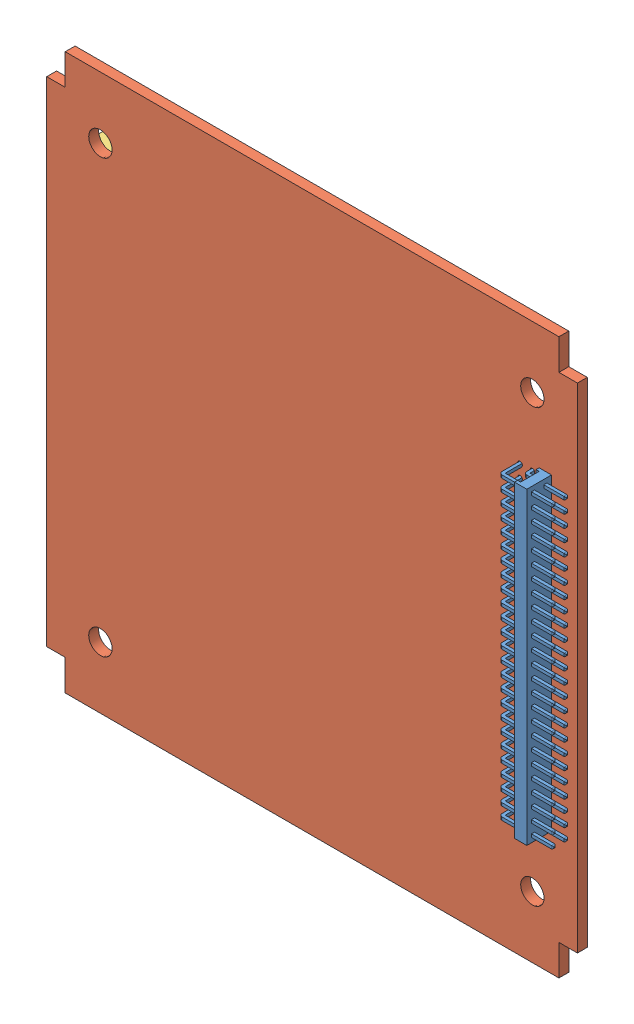
SolidWorks assembly B3_LDM_board, configuration ﾃﾞﾌｫﾙﾄ. Lengths in mm.
Overall size (86 90 16.2).
4 component instances, 3 part files, 9 mates.
Components (placement in the parent):
- B3_50pinL-2: B3_50pinL [Default] at (33.5663 23.7961 119.8153) x (0 -1 0) z (0 0 1) size (50 8.75 7)
- B3_internal_board_LDM-1: B3_internal_board_LDM [ﾃﾞﾌｫﾙﾄ] at (39.7663 43.7961 118.2153) size (86 90 1.6)
- MMCX002-1: MMCX002 [ﾃﾞﾌｫﾙﾄ] at (-44.7337 4.2961 113.4153) x (0 0 1) z (0 1 0) size (10.6 8.66 27)
- MMCX002-2: MMCX002 [ﾃﾞﾌｫﾙﾄ] at (-37.7337 -6.7039 113.4153) x (0 0 1) z (0 -1 0) size (10.6 8.66 27)
Mates (geometry in assembly coordinates):
- 一致1: coincident anti-aligned: plane of B3_50pinL-2 through (35.5663 23.7961 119.8153) normal (0 0 -1); plane of B3_internal_board_LDM-1 through (39.7663 43.7961 119.8153) normal (0 0 1)
- 距離1: distance = 20 mm aligned: plane of B3_50pinL-2 through (35.5663 23.7961 119.8153) normal (0 1 0); plane of B3_internal_board_LDM-1 through (36.7663 43.7961 119.8153) normal (0 1 0)
- 距離2: distance = 4.2 mm aligned: plane of B3_internal_board_LDM-1 through (39.7663 38.7961 119.8153) normal (1 0 0); plane of B3_50pinL-2 through (35.5663 23.7961 119.8153) normal (1 0 0)
- 一致56: coincident anti-aligned: plane of B3_internal_board_LDM-1 through (39.7663 43.7961 118.2153) normal (0 0 -1); plane of MMCX002-1 through (-44.7337 4.2961 118.2153) normal (0 0 1)
- 距離11: distance = 1.5 mm aligned: plane of MMCX002-1 through (-44.7337 4.2961 113.4153) normal (-1 0 0); plane of B3_internal_board_LDM-1 through (-46.2337 43.7961 119.8153) normal (-1 0 0)
- 一致60: coincident anti-aligned: plane of B3_internal_board_LDM-1 through (39.7663 43.7961 118.2153) normal (0 0 -1); plane of MMCX002-2 through (-37.7337 -6.7039 118.2153) normal (0 0 1)
- 距離14: distance = 1.5 mm aligned: plane of B3_internal_board_LDM-1 through (-46.2337 43.7961 119.8153) normal (-1 0 0); plane of MMCX002-2 through (-44.7337 -6.7039 113.4153) normal (-1 0 0)
- 距離15: distance = 47 mm aligned: plane of MMCX002-2 through (-44.7337 -3.2039 108.9153) normal (0 1 0); plane of B3_internal_board_LDM-1 through (36.7663 43.7961 119.8153) normal (0 1 0)
- 距離16: distance = 47 mm aligned: plane of MMCX002-1 through (-37.7337 0.7961 108.9153) normal (0 -1 0); plane of B3_internal_board_LDM-1 through (36.7663 -46.2039 119.8153) normal (0 -1 0)
